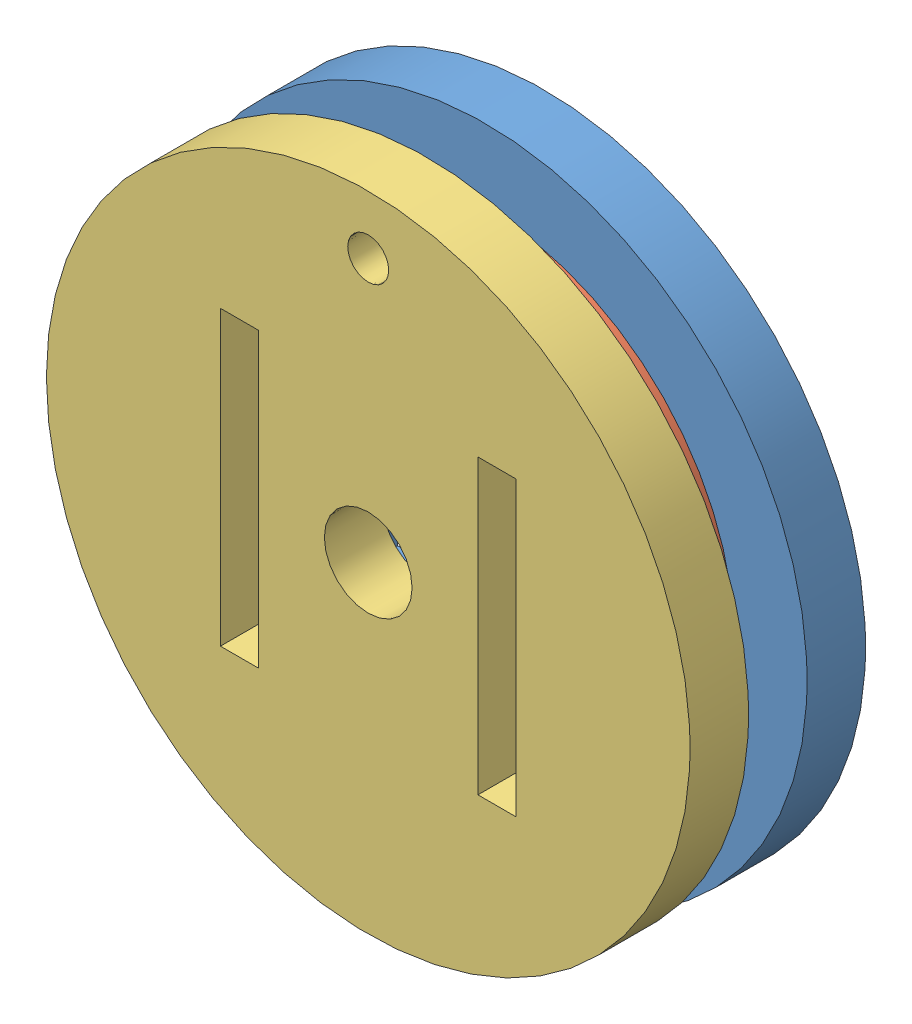
SolidWorks assembly servoPulleyStd, configuration Default. Lengths in mm.
Overall size (22 22 6).
3 component instances, 3 part files, 6 mates.
Components (placement in the parent):
- servoPulleyStd1-1: servoPulleyStd1 [Default] at (4.0524 13.5476 17.6777) size (22 22 2)
- servoPulleyStd2-1: servoPulleyStd2 [Default] at (4.0524 13.5476 19.6777) size (17 17 2)
- servoPulleyStd3-1: servoPulleyStd3 [Default] at (4.0524 13.5476 21.6777) size (22 22 2)
Mates (geometry in assembly coordinates):
- Concentric1: concentric aligned: circle of servoPulleyStd1-1; circle of servoPulleyStd2-1
- Concentric2: concentric aligned: circle of servoPulleyStd1-1; circle of servoPulleyStd3-1
- Parallel1: parallel aligned: plane of servoPulleyStd2-1 through (9.0524 8.5476 21.6777) normal (-1 0 0); plane of servoPulleyStd3-1 through (9.1024 18.5476 23.6777) normal (-1 0 0)
- Parallel2: parallel aligned: plane of servoPulleyStd1-1 through (9.0524 8.5476 19.6777) normal (-1 0 0); plane of servoPulleyStd2-1 through (9.0524 8.5476 21.6777) normal (-1 0 0)
- Coincident2: coincident anti-aligned: plane of servoPulleyStd2-1 through (4.0524 13.5476 21.6777) normal (0 0 1); plane of servoPulleyStd3-1 through (4.0524 13.5476 21.6777) normal (0 0 -1)
- Coincident3: coincident anti-aligned: plane of servoPulleyStd1-1 through (4.0524 13.5476 19.6777) normal (0 0 1); plane of servoPulleyStd2-1 through (4.0524 13.5476 19.6777) normal (0 0 -1)
